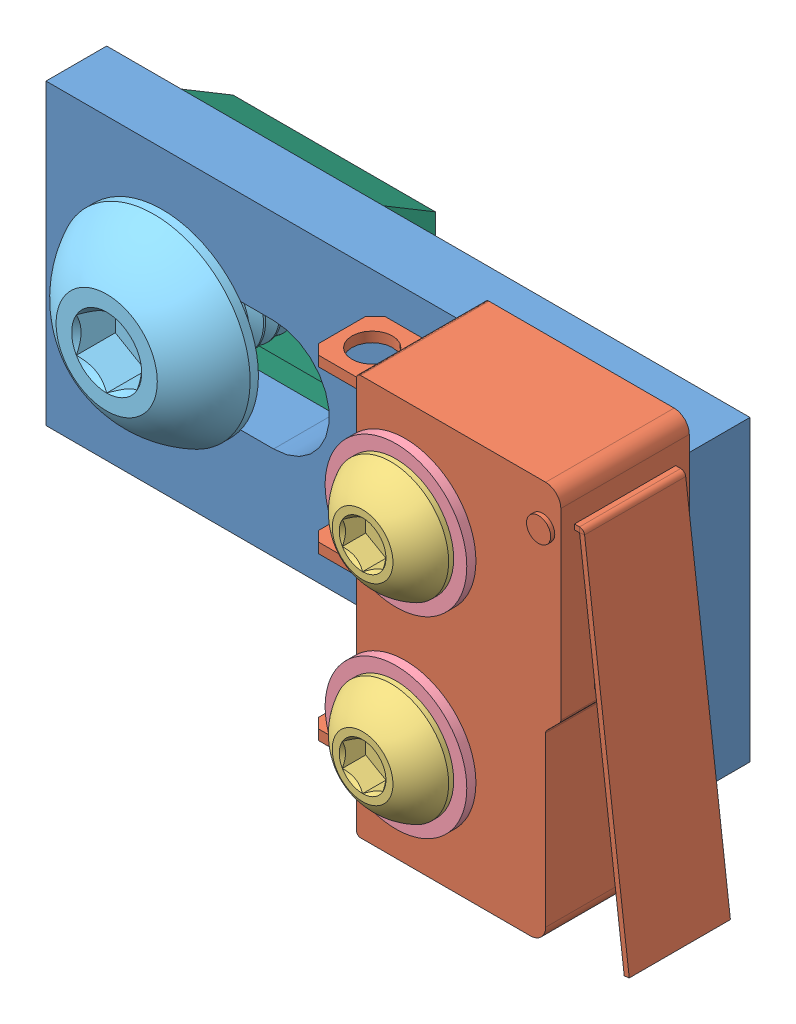
SolidWorks assembly Z_Limit_Assembly, configuration Default. Lengths in mm.
Overall size (34.71 19.86 17.27).
8 component instances, 6 part files, 16 mates.
Components (placement in the parent):
- Limitt Switch Mounting Plate-1: Limitt Switch Mounting Plate [Default] at origin size (31.8 14.75 3)
- Micro Switch Button-1: Micro Switch Button [Default] at (26.7 7.475 6.375) x (0 0 -1) z (0 -1 0) size (6.75 16.71 19.86)
- 3mmX10mm_Buttonhead(McMaster_94500A223)-1: 3mmX10mm_Buttonhead(McMaster_94500A223) [94500A223] at (24.3 11.375 11.65) size (5.7 5.7 11.96)
- 3mmX10mm_Buttonhead(McMaster_94500A223)-2: 3mmX10mm_Buttonhead(McMaster_94500A223) [94500A223] at (24.3 1.875 11.65) size (5.7 5.7 11.96)
- M3_Flat_Washer(McMaster_93475A210)-1: M3_Flat_Washer(McMaster_93475A210) [93475A210] at (24.3 11.375 10) size (7 7 0.45)
- M3_Flat_Washer(McMaster_93475A210)-2: M3_Flat_Washer(McMaster_93475A210) [93475A210] at (24.3 1.875 10) size (7 7 0.45)
- 5mmX8mm_Buttonhead(McMaster_94500A230)-1: 5mmX8mm_Buttonhead(McMaster_94500A230) [94500A230] at (5.75 7.375 5.75) size (9.5 9.5 11.19)
- HNTTSN5-5-1: HNTTSN5-5 [Default] at (5.75 7.375 -1.2) x (0 0 1) z (-1 0 0) size (4.3 10 10)
Mates (geometry in assembly coordinates):
- Concentric2: concentric aligned: cylinder of Limitt Switch Mounting Plate-1 through (24.3 1.875 3) axis (0 0 -1) radius 1.5; cylinder of Micro Switch Button-1 through (24.3 1.875 9.55) axis (0 0 -1) radius 1.35
- Parallel2: parallel aligned: plane of Limitt Switch Mounting Plate-1 through (0 0 3) normal (0 -1 0); plane of Micro Switch Button-1 through (30.5 -3.325 3.2) normal (0 -1 0)
- Coincident2: coincident anti-aligned: plane of Limitt Switch Mounting Plate-1 through (0 0 3) normal (0 0 1); plane of Micro Switch Button-1 through (24.3 1.875 3) normal (0 0 -1)
- Concentric4: concentric anti-aligned: cylinder of Limitt Switch Mounting Plate-1 through (5.75 7.375 3) axis (0 0 -1) radius 2.75; cylinder of 5mmX8mm_Buttonhead(McMaster_94500A230)-1 through (5.75 7.375 5.75) axis (0 0 1) radius 4.75
- Coincident3: coincident anti-aligned: plane of Limitt Switch Mounting Plate-1 through (0 0 3) normal (0 0 1); plane of 5mmX8mm_Buttonhead(McMaster_94500A230)-1 through (5.75 2.625 3) normal (0 0 -1)
- Concentric5: concentric anti-aligned: cylinder of 5mmX8mm_Buttonhead(McMaster_94500A230)-1 through (5.75 7.375 5.75) axis (0 0 1) radius 4.75; cylinder of HNTTSN5-5-1 through (5.75 7.375 -1.2) axis (0 0 -1) radius 2.067
- Parallel3: parallel aligned: plane of Limitt Switch Mounting Plate-1 through (0 0 3) normal (-1 0 0); plane of HNTTSN5-5-1 through (0.75 7.375 -1.2) normal (-1 0 0)
- Distance1: distance = 2 mm anti-aligned: plane of HNTTSN5-5-1 through (0.75 2.375 -2) normal (0 0 1); plane of Limitt Switch Mounting Plate-1 through (0 0 0) normal (0 0 -1)
- Concentric6: concentric anti-aligned: cylinder of Micro Switch Button-1 through (24.3 11.375 9.55) axis (0 0 -1) radius 1.35; cylinder of 3mmX10mm_Buttonhead(McMaster_94500A223)-1 through (24.3 11.375 11.65) axis (0 0 1) radius 2.85
- Concentric7: concentric anti-aligned: cylinder of Micro Switch Button-1 through (24.3 11.375 9.55) axis (0 0 -1) radius 1.35; cylinder of M3_Flat_Washer(McMaster_93475A210)-1 through (24.3 11.375 9.55) axis (0 0 1) radius 1.6
- Concentric8: concentric anti-aligned: cylinder of Micro Switch Button-1 through (24.3 1.875 9.55) axis (0 0 -1) radius 1.35; cylinder of 3mmX10mm_Buttonhead(McMaster_94500A223)-2 through (24.3 1.875 11.65) axis (0 0 1) radius 2.85
- Concentric9: concentric anti-aligned: cylinder of Micro Switch Button-1 through (24.3 1.875 9.55) axis (0 0 -1) radius 1.35; cylinder of M3_Flat_Washer(McMaster_93475A210)-2 through (24.3 1.875 9.55) axis (0 0 1) radius 1.6
- Coincident6: coincident anti-aligned: plane of Micro Switch Button-1 through (22.1 16.275 9.55) normal (0 0 1); plane of M3_Flat_Washer(McMaster_93475A210)-2 through (24.3 1.875 9.55) normal (0 0 -1)
- Coincident7: coincident anti-aligned: plane of 3mmX10mm_Buttonhead(McMaster_94500A223)-2 through (24.3 -0.975 10) normal (0 0 -1); plane of M3_Flat_Washer(McMaster_93475A210)-2 through (24.3 1.875 10) normal (0 0 1)
- Coincident8: coincident anti-aligned: plane of Micro Switch Button-1 through (22.1 16.275 9.55) normal (0 0 1); plane of M3_Flat_Washer(McMaster_93475A210)-1 through (24.3 11.375 9.55) normal (0 0 -1)
- Coincident9: coincident anti-aligned: plane of 3mmX10mm_Buttonhead(McMaster_94500A223)-1 through (24.3 8.525 10) normal (0 0 -1); plane of M3_Flat_Washer(McMaster_93475A210)-1 through (24.3 11.375 10) normal (0 0 1)
